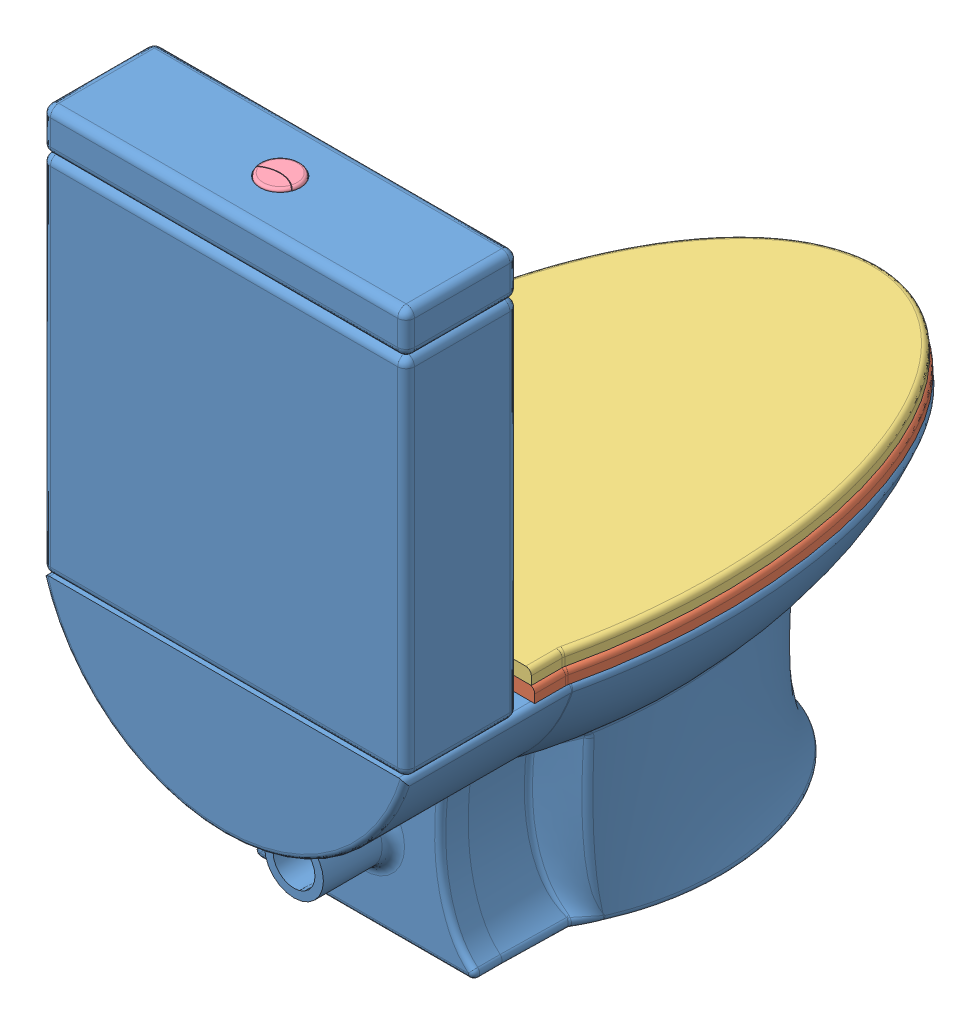
SolidWorks assembly wc, configuration Default. Lengths in mm.
Overall size (163.4 246.19 247.5).
4 component instances, 4 part files, 10 mates.
Components (placement in the parent):
- WC-1: WC [Default] at (2.1048 14.0792 313.5167) size (160.86 245.12 245.77)
- wc saddle-1: wc saddle [Default] at (2.2353 13.0792 313.3727) size (162.18 215.12 247.36)
- Cover-1: Cover [Default] at (1.0205 18.0792 313.3727) size (162.18 215.12 247.36)
- Part5^wc-1: Part5^wc [Default] at (2.1048 257.0792 313.5167) x (1 0 0) z (0 1 0) size (14.12 14.12 3.06) (virtual)
Mates (geometry in assembly coordinates):
- Coincident1: coincident: plane of WC-1 through (2.1048 114.0792 313.5167) normal (0 1 0); plane of wc saddle-1 through (-7.4511 114.0792 150.597) normal (0 -1 0)
- Coincident3: coincident: line of wc saddle-1 through (-69.2512 119.0792 338.2355) axis (1 0 0); line of Cover-1 through (-72.466 119.0792 338.2355) axis (1 0 0)
- Distance1: distance = 7.1438 mm: plane of WC-1 through (-72.8391 244.0792 345.3793) normal (0 0 -1); plane of wc saddle-1 through (-71.2512 119.0792 338.2355) normal (0 0 1)
- Distance2: distance = 1.3269 mm: plane of wc saddle-1 through (55.9189 119.0792 338.2355) normal (1 0 0); plane of WC-1 through (57.2458 244.0792 385.5167) normal (1 0 0)
- Distance3: distance = 1.2147 mm: plane of wc saddle-1 through (55.9189 119.0792 338.2355) normal (1 0 0); plane of Cover-1 through (54.7042 124.0792 338.2355) normal (1 0 0)
- LimitAngle1: limit planar angle = 0 rad: plane of wc saddle-1 through (-7.4511 119.0792 150.597) normal (0 1 0); plane of Cover-1 through (-8.6659 119.0792 150.597) normal (0 -1 0)
- InPlace1: in place: plane of WC-1 through (-7.7967 257.0792 365.448) normal (0 1 0); plane of ? through (0 257.0792 0) normal (0 1 0); moOrthogonalPlaneRef_w of WC-1 through (-7.7967 257.0792 365.448) normal (0 1 0); plane of ? through (0 257.0792 0) normal (0 0 -1); plane of WC-1 through (-7.7967 257.0792 365.448) normal (0 1 0); plane of ? through (0 257.0792 0) normal (1 0 0); plane of WC-1 through (-7.7967 257.0792 365.448) normal (0 1 0); unknown of Part5^wc-1
- Coincident9: coincident: plane of WC-1; plane of Part5^wc-1
- Coincident10: coincident: moOrthogonalPlaneRef_w of WC-1 through (2.1048 257.0792 313.5167) normal (0 0 -1); plane of Part5^wc-1 through (2.1048 257.0792 313.5167) normal (0 0 -1)
- Coincident11: coincident: moOrthogonalPlaneRef_w of WC-1 through (2.1048 257.0792 313.5167) normal (-1 0 0); plane of Part5^wc-1 through (2.1048 257.0792 313.5167) normal (1 0 0)
